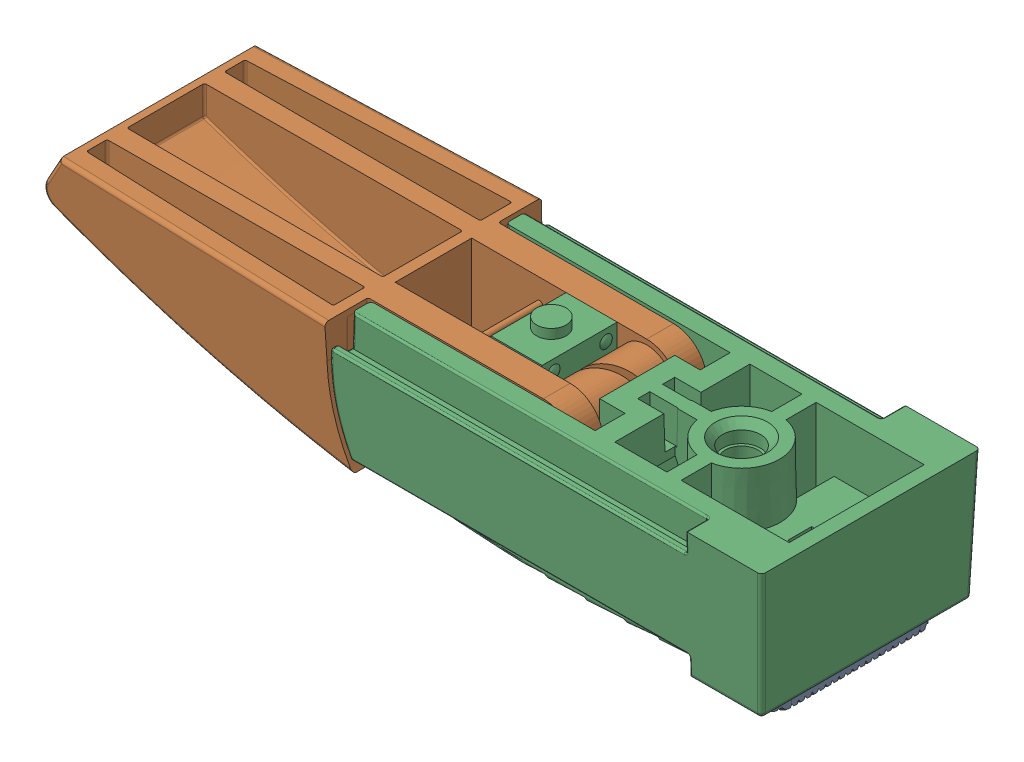
SolidWorks assembly 87646929_3, configuration По умолчанию. Lengths in mm.
Overall size (76.83 16.23 23.05).
3 component instances, 3 part files, 0 mates.
Components (placement in the parent):
- 60842027-1: 60842027 [По умолчанию] at (-13.1638 33.8211 0) x (-1 0 0) z (0 0 1) size (7.8 7.5 17.5)
- 87646931-1: 87646931 [По умолчанию] at (30.061 -56.7212 0) size (52.7 12.81 22.79)
- 87646929-1: 87646929 [По умолчанию] at (30.061 -56.7211 0) size (45.66 15.15 23.05)
